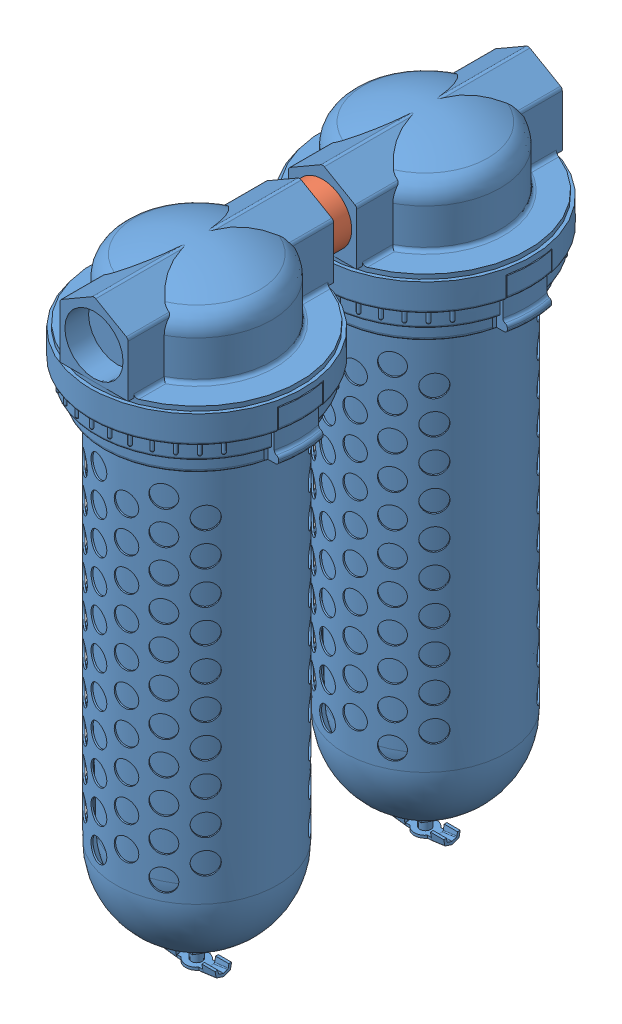
SolidWorks assembly ReadingTech_4P-090-P08-DCP, configuration Default. Lengths in mm.
Overall size (121.86 360.29 252.73).
3 component instances, 2 part files, 2 mates.
Components (placement in the parent):
- ReadingTech_3P-090-P08-P-1: ReadingTech_3P-090-P08-P [Default] at (-74.64 -213.4967 26.1885) size (121.86 360.29 121.67)
- ReadingTech_3P-090-P08-P-2: ReadingTech_3P-090-P08-P [Default] at (-74.64 -213.4967 -104.8755) size (121.86 360.29 121.67)
- ReadingTech- 90,150cfm_connector_1in-1: ReadingTech- 90,150cfm_connector_1in [Default] at (-74.64 175.5043 -32.7395) x (1 0 0) z (0 1 0) size (33.4 13.21 33.4)
Mates (geometry in assembly coordinates):
- Coincident1: coincident anti-aligned: circle of ReadingTech_3P-090-P08-P-2; circle of ReadingTech- 90,150cfm_connector_1in-1
- Coincident2: coincident aligned: circle of ReadingTech_3P-090-P08-P-1; circle of ReadingTech- 90,150cfm_connector_1in-1
